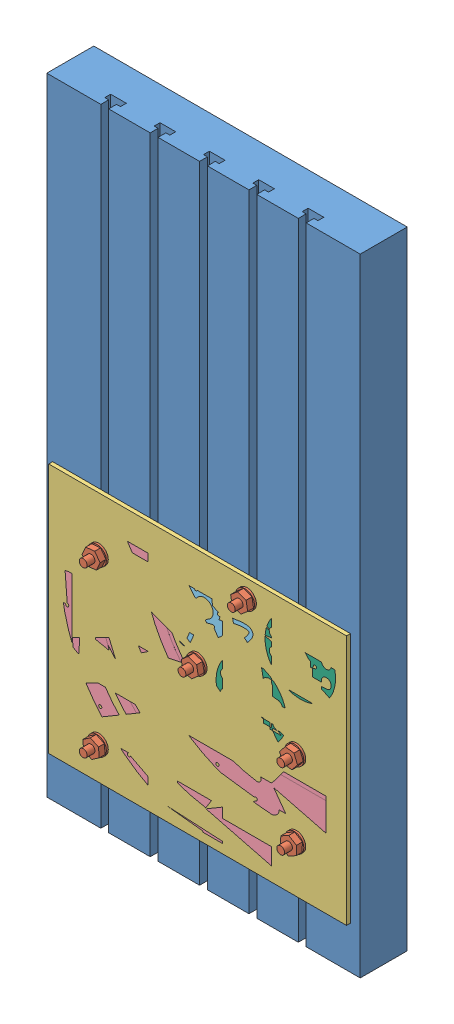
SolidWorks assembly CAM_Assem1, configuration Default. Lengths in mm.
Overall size (508 1016 111.12).
14 component instances, 7 part files, 23 mates.
Components (placement in the parent):
- Table^CAM_Assem1-1: Table^CAM_Assem1 [Default] at (-1673.8784 81.0862 0) x (-1 0 0) z (0 0 1) size (508 1016 76.2) (virtual)
- TBolt^CAM_Assem1-1: TBolt^CAM_Assem1 [Default] at (136.7534 -791.3929 9.525) x (0.837816 0.545952 0) z (0 0 1) size (30.48 30.48 50.8) (virtual)
- TBolt^CAM_Assem1-2: TBolt^CAM_Assem1 [Default] at (-773.0398 -409.4619 9.525) x (-0.05678 -0.998387 0) z (0 0 1) size (30.48 30.48 50.8) (virtual)
- TBolt^CAM_Assem1-4: TBolt^CAM_Assem1 [Default] at (-316.7695 -848.4394 9.525) x (0.776315 -0.630345 0) z (0 0 1) size (30.48 30.48 50.8) (virtual)
- TBolt^CAM_Assem1-3: TBolt^CAM_Assem1 [Default] at (-166.5778 281.6324 9.525) x (-0.999439 0.033481 0) z (0 0 1) size (30.48 30.48 50.8) (virtual)
- TBolt^CAM_Assem1-5: TBolt^CAM_Assem1 [Default] at (388.6003 -782.1929 9.525) x (0.710057 0.704144 0) z (0 0 1) size (30.48 30.48 50.8) (virtual)
- TBolt^CAM_Assem1-6: TBolt^CAM_Assem1 [Default] at (514.9212 -230.4549 9.525) x (-0.040214 0.999191 0) z (0 0 1) size (30.48 30.48 50.8) (virtual)
- Stock^CAM_Assem1-1: Stock^CAM_Assem1 [Default] at (-31.8259 -275.7531 9.525) x (1 0 0) z (0 1 0) size (482.6 6.35 406.4) (virtual)
- Side_Plate-2: Side_Plate [Default] at (-47.9926 -290.0981 3.175) size (342.58 266.38 6.35)
- Side_Plate-3: Side_Plate [Default] at (39.6644 -199.7789 3.175) size (342.58 266.38 6.35)
- Spoke-1: Spoke [Default] at (-81.6463 -230.6639 3.175) x (0.811307 0.58462 0) z (0 0 1) size (138.51 131.05 6.35)
- End_Plate-1: End_Plate [Default] at (-5.4301 -322.3658 9.525) x (0 0 -1) z (1 0 0) size (6.35 114.3 114.3)
- End_Plate-2: End_Plate [Default] at (73.7458 -224.1363 9.525) x (0 0 -1) z (1 0 0) size (6.35 114.3 114.3)
- Contour^CAM_Assem1-1: Contour^CAM_Assem1 [Default] at (-1673.8784 81.0862 0) x (-1 0 0) z (0 0 1) size (445.27 394.72 9.53) (hidden, virtual)
Mates (geometry in assembly coordinates):
- Coincident1: coincident aligned: plane of Side_Plate-2 through (-47.9926 -290.0981 9.525) normal (0 0 1); plane of Side_Plate-3 through (39.6644 -199.7789 9.525) normal (0 0 1)
- Coincident2: coincident aligned: plane of Side_Plate-2 through (-47.9926 -290.0981 9.525) normal (0 0 1); plane of Stock^CAM_Assem1-1 through (-31.8259 -275.7531 9.525) normal (0 0 1)
- Coincident7: coincident anti-aligned: plane of Stock^CAM_Assem1-1 through (-31.8259 -275.7531 9.525) normal (0 0 1); plane of TBolt^CAM_Assem1-1 through (-92.5868 -314.009 9.525) normal (0 0 -1)
- Width1: width: plane of Table^CAM_Assem1-1 through (-86.2368 382.3597 -12.7) normal (-1 0 0); plane of Table^CAM_Assem1-1 through (-98.9368 382.3597 -12.7) normal (1 0 0); cylinder of TBolt^CAM_Assem1-1 through (-92.5868 -314.009 -15.875) axis (0 0 1) radius 6.35
- Width2: width anti-aligned: plane of Stock^CAM_Assem1-1 through (-333.8868 -155.0214 3.175) normal (-1 0 0); plane of Stock^CAM_Assem1-1 through (148.7132 -155.0214 3.175) normal (1 0 0); plane of Table^CAM_Assem1-1 through (161.4132 382.3597 -76.2) normal (1 0 0); plane of Table^CAM_Assem1-1 through (-346.5868 382.3597 -76.2) normal (-1 0 0)
- Coincident9: coincident anti-aligned: plane of Stock^CAM_Assem1-1 through (-31.8259 -275.7531 9.525) normal (0 0 1); plane of TBolt^CAM_Assem1-2 through (-252.6068 -507.6546 9.525) normal (0 0 -1)
- Coincident10: coincident anti-aligned: plane of Stock^CAM_Assem1-1 through (-31.8259 -275.7531 9.525) normal (0 0 1); plane of TBolt^CAM_Assem1-3 through (-252.6068 -240.949 9.525) normal (0 0 -1)
- Coincident11: coincident anti-aligned: plane of Stock^CAM_Assem1-1 through (-31.8259 -275.7531 9.525) normal (0 0 1); plane of TBolt^CAM_Assem1-4 through (67.4332 -483.9113 9.525) normal (0 0 -1)
- Width3: width: plane of Table^CAM_Assem1-1 through (-246.2568 81.0862 -12.7) normal (-1 0 0); plane of Table^CAM_Assem1-1 through (-258.9568 81.0862 -12.7) normal (1 0 0); cylinder of TBolt^CAM_Assem1-2 through (-252.6068 -507.6546 34.925) axis (0 0 -1) radius 6.35
- Width4: width: plane of Table^CAM_Assem1-1 through (73.7832 81.0862 -12.7) normal (-1 0 0); plane of Table^CAM_Assem1-1 through (61.0832 81.0862 -12.7) normal (1 0 0); cylinder of TBolt^CAM_Assem1-4 through (67.4332 -483.9113 34.925) axis (0 0 -1) radius 6.35
- Width5: width: plane of Table^CAM_Assem1-1 through (-246.2568 81.0862 -12.7) normal (-1 0 0); plane of Table^CAM_Assem1-1 through (-258.9568 81.0862 -12.7) normal (1 0 0); cylinder of TBolt^CAM_Assem1-3 through (-252.6068 -240.949 34.925) axis (0 0 -1) radius 6.35
- Distance1: distance = 3.175 mm anti-aligned: plane of Stock^CAM_Assem1-1 through (-31.8259 -275.7531 3.175) normal (0 0 -1); plane of Table^CAM_Assem1-1 through (-1673.8784 81.0862 0) normal (0 0 1)
- InPlace2: in place: plane of ? through (-1673.8784 81.0862 0) normal (0 0 1); plane of assembly through (0 0 0) normal (0 0 1); moOrthogonalPlaneRef_w of ? through (-1673.8784 81.0862 0) normal (0 0 1); plane of assembly through (0 0 0) normal (0 1 0); plane of ? through (-1673.8784 81.0862 0) normal (0 0 1); plane of assembly through (0 0 0) normal (1 0 0); plane of ? through (-1673.8784 81.0862 0) normal (0 0 1); unknown of ?
- Coincident13: coincident aligned: plane of Table^CAM_Assem1-1; plane of Contour^CAM_Assem1-1
- Coincident14: coincident aligned: moOrthogonalPlaneRef_w of Table^CAM_Assem1-1 through (-1673.8784 81.0862 0) normal (0 -1 0); plane of Contour^CAM_Assem1-1
- Coincident15: coincident anti-aligned: moOrthogonalPlaneRef_w of Table^CAM_Assem1-1 through (-1673.8784 81.0862 0) normal (1 0 0); plane of Contour^CAM_Assem1-1
- Coincident12: coincident aligned: plane of Stock^CAM_Assem1-1 through (-31.8259 -275.7531 9.525) normal (0 0 1); plane of End_Plate-1 through (-5.4301 -322.3658 9.525) normal (0 0 1)
- Coincident13: coincident aligned: plane of Stock^CAM_Assem1-1 through (-31.8259 -275.7531 9.525) normal (0 0 1); plane of End_Plate-2 through (73.7458 -224.1363 9.525) normal (0 0 1)
- Coincident15: coincident aligned: plane of Stock^CAM_Assem1-1 through (-31.8259 -275.7531 9.525) normal (0 0 1); plane of Spoke-1 through (-81.6463 -230.6639 9.525) normal (0 0 1)
- Width6: width: plane of Table^CAM_Assem1-1 through (73.7832 81.0862 -12.7) normal (-1 0 0); plane of Table^CAM_Assem1-1 through (61.0832 81.0862 -12.7) normal (1 0 0); cylinder of TBolt^CAM_Assem1-5 through (67.4332 -361.0706 -15.875) axis (0 0 1) radius 6.35
- Coincident16: coincident aligned: plane of TBolt^CAM_Assem1-3 through (-252.6068 -240.949 34.925) normal (0 0 1); plane of TBolt^CAM_Assem1-5 through (67.4332 -361.0706 34.925) normal (0 0 1)
- Coincident17: coincident aligned: plane of TBolt^CAM_Assem1-3 through (-252.6068 -240.949 34.925) normal (0 0 1); plane of TBolt^CAM_Assem1-6 through (-12.5768 -183.1456 34.925) normal (0 0 1)
- Width7: width: plane of Table^CAM_Assem1-1 through (-6.2268 382.3597 -12.7) normal (-1 0 0); plane of Table^CAM_Assem1-1 through (-18.9268 382.3597 -12.7) normal (1 0 0); cylinder of TBolt^CAM_Assem1-6 through (-12.5768 -183.1456 -15.875) axis (0 0 1) radius 6.35
